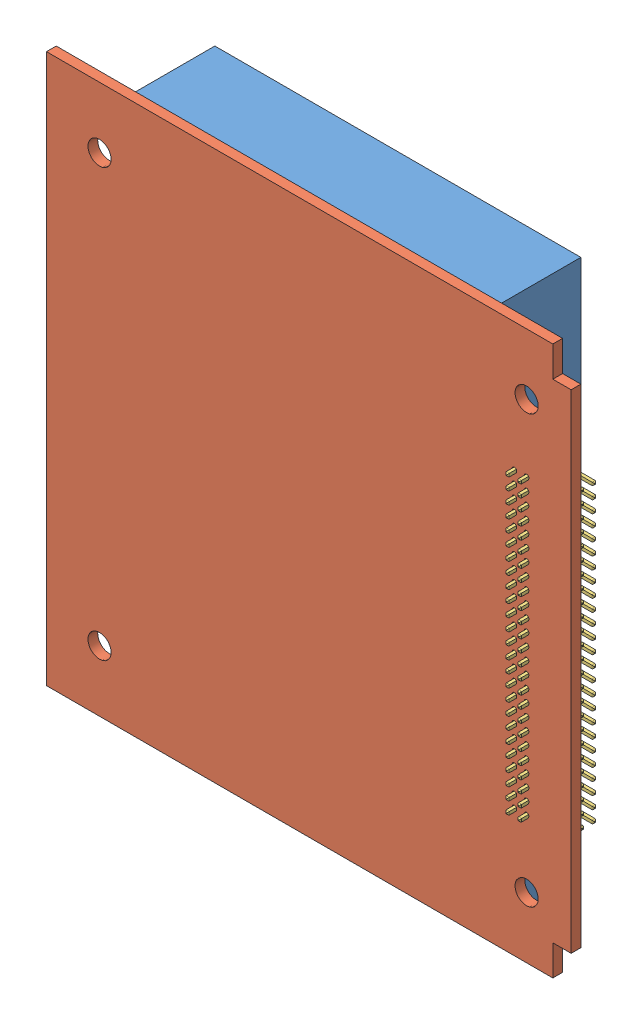
SolidWorks assembly B3_COM_board, configuration Default. Lengths in mm.
Overall size (86 90 16).
4 component instances, 3 part files, 9 mates.
Components (placement in the parent):
- ADDNICS_TRX-1: ADDNICS_TRX [Default] at (-67.5189 -47.3366 82.2646) x (0 0 1) z (0 -1 0) size (13 60 38)
- B3_internal_board_com-1: B3_internal_board_com [ﾃﾞﾌｫﾙﾄ] at (-24.5189 -47.3366 88.7646) size (86 90 1.6)
- B3_50pinL-1: B3_50pinL [Default] at (-30.7189 -117.3366 88.7646) x (0 1 0) z (0 0 -1) size (50 8.75 7)
- ADDNICS_TRX-2: ADDNICS_TRX [Default] at (-67.5189 -137.3366 82.2646) x (0 0 1) z (0 1 0) size (13 60 38)
Mates (geometry in assembly coordinates):
- Coincident1: coincident anti-aligned: plane of ADDNICS_TRX-1 through (-97.5189 -85.3366 88.7646) normal (0 0 1); plane of B3_internal_board_com-1 through (-24.5189 -47.3366 88.7646) normal (0 0 -1)
- Distance1: distance = 13 mm aligned: plane of ADDNICS_TRX-1 through (-97.5189 -85.3366 75.7646) normal (-1 0 0); plane of B3_internal_board_com-1 through (-110.5189 -47.3366 90.3646) normal (-1 0 0)
- Coincident2: coincident anti-aligned: plane of B3_internal_board_com-1 through (-24.5189 -47.3366 88.7646) normal (0 0 -1); plane of B3_50pinL-1 through (-28.7189 -117.3366 88.7646) normal (0 0 1)
- Distance3: distance = 20 mm aligned: plane of B3_50pinL-1 through (-28.7189 -117.3366 88.7646) normal (0 -1 0); plane of B3_internal_board_com-1 through (-27.5189 -137.3366 90.3646) normal (0 -1 0)
- Distance4: distance = 4.2 mm aligned: plane of B3_50pinL-1 through (-28.7189 -117.3366 88.7646) normal (1 0 0); plane of B3_internal_board_com-1 through (-24.5189 -52.3366 90.3646) normal (1 0 0)
- 一致1: coincident aligned: plane of ADDNICS_TRX-1 through (-67.5189 -47.3366 82.2646) normal (0 1 0); plane of B3_internal_board_com-1 through (-27.5189 -47.3366 90.3646) normal (0 1 0)
- 一致2: coincident anti-aligned: plane of B3_internal_board_com-1 through (-24.5189 -47.3366 88.7646) normal (0 0 -1); plane of ADDNICS_TRX-2 through (-37.5189 -99.3366 88.7646) normal (0 0 1)
- 一致3: coincident: line of B3_internal_board_com-1 through (-103.5189 -137.3366 88.7646) axis (1 0 0); plane of ADDNICS_TRX-2 through (-67.5189 -137.3366 82.2646) normal (0 -1 0)
- 一致4: coincident aligned: plane of ADDNICS_TRX-1 through (-97.5189 -85.3366 75.7646) normal (-1 0 0); plane of ADDNICS_TRX-2 through (-97.5189 -99.3366 75.7646) normal (-1 0 0)
